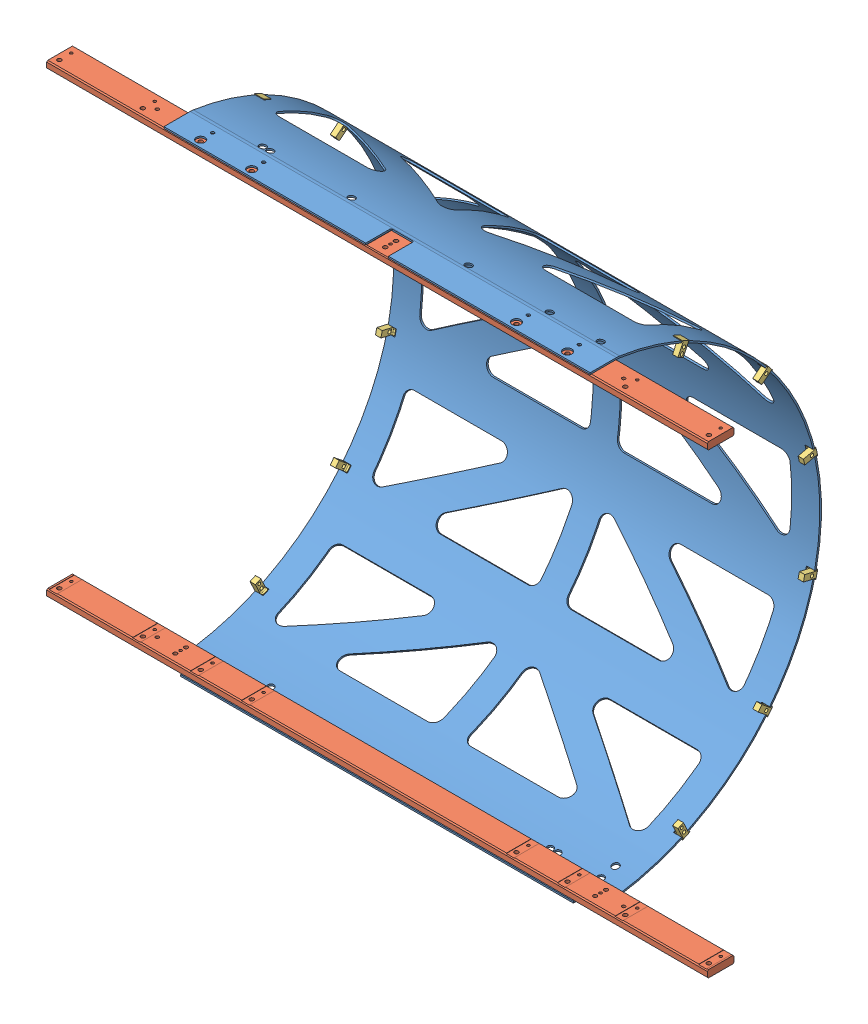
SolidWorks assembly VTX-Spaceframe Assy, configuration Default. Lengths in mm.
Overall size (600 431.91 213.56).
16 component instances, 4 part files, 14 mates.
Components (placement in the parent):
- VTX-Spaceframe Shell-1: VTX-Spaceframe Shell [Default] at origin size (393.6 431.91 213.56)
- VTX-Barrel Spaceframe joint tab-16: VTX-Barrel Spaceframe joint tab [top] at origin size (600 6.71 24.73)
- VTX-Barrel Spaceframe joint tab-15: VTX-Barrel Spaceframe joint tab [bottom] x (-1 0 0) z (0 0 1) size (600 6.71 24.73)
- Spaceframe disk mounting block 1-8: Spaceframe disk mounting block 1 [pin-threaded holes] at (195.09 -191.7412 -89.4104) x (0 -0.422618 0.906308) z (0 0.906308 0.422618) size (7.5 8.75 12)
- Spaceframe disk mounting block 1-2: Spaceframe disk mounting block 1 [pin-threaded holes] at (-195.09 -191.7412 -89.4104) x (0 0.422618 -0.906308) z (0 0.906308 0.422618) size (7.5 8.75 12)
- Spaceframe disk mounting block 1-9: Spaceframe disk mounting block 1 [threaded hole only] at (195.09 -133.1409 -164.4153) x (0 -0.777146 0.62932) z (0 0.62932 0.777146) size (7.5 8.75 12)
- Spaceframe disk mounting block 1-10: Spaceframe disk mounting block 1 [threaded hole only] at (195.09 -47.5913 -206.1407) x (0 -0.97437 0.224951) z (0 0.224951 0.97437) size (7.5 8.75 12)
- Spaceframe disk mounting block 1-11: Spaceframe disk mounting block 1 [threaded hole only] at (195.09 47.5913 -206.1407) x (0 -0.97437 -0.224951) z (0 -0.224951 0.97437) size (7.5 8.75 12)
- Spaceframe disk mounting block 1-12: Spaceframe disk mounting block 1 [threaded hole only] at (195.09 133.1409 -164.4153) x (0 -0.777146 -0.62932) z (0 -0.62932 0.777146) size (7.5 8.75 12)
- Spaceframe disk mounting block 1-13: Spaceframe disk mounting block 1 [slot for pin + threaded hole] at (195.09 191.7412 -89.4104) x (0 -0.422618 -0.906308) z (0 -0.906308 0.422618) size (7.5 8.75 12)
- Spaceframe disk mounting block 1-14: Spaceframe disk mounting block 1 [threaded hole only] at (-195.09 -133.1409 -164.4153) x (0 0.777146 -0.62932) z (0 0.62932 0.777146) size (7.5 8.75 12)
- Spaceframe disk mounting block 1-15: Spaceframe disk mounting block 1 [threaded hole only] at (-195.09 -47.5913 -206.1407) x (0 0.97437 -0.224951) z (0 0.224951 0.97437) size (7.5 8.75 12)
- Spaceframe disk mounting block 1-16: Spaceframe disk mounting block 1 [threaded hole only] at (-195.09 47.5913 -206.1407) x (0 0.97437 0.224951) z (0 -0.224951 0.97437) size (7.5 8.75 12)
- Spaceframe disk mounting block 1-17: Spaceframe disk mounting block 1 [threaded hole only] at (-195.09 133.1409 -164.4153) x (0 0.777146 0.62932) z (0 -0.62932 0.777146) size (7.5 8.75 12)
- Spaceframe disk mounting block 1-18: Spaceframe disk mounting block 1 [slot for pin + threaded hole] at (-195.09 191.7412 -89.4104) x (0 0.422618 0.906308) z (0 -0.906308 0.422618) size (7.5 8.75 12)
- Adhesive-1: Adhesive [Default] at origin
Mates (geometry in assembly coordinates):
- Coincident77: coincident aligned: plane of VTX-Barrel Spaceframe joint tab-16 through (0 0 0) normal (0 0 1); plane of assembly through (0 0 0) normal (0 0 1)
- Coincident78: coincident aligned: plane of VTX-Barrel Spaceframe joint tab-16 through (0 0 0) normal (0 1 0); plane of assembly through (0 0 0) normal (0 1 0)
- Coincident79: coincident aligned: plane of VTX-Barrel Spaceframe joint tab-16 through (0 0 0) normal (1 0 0); plane of assembly through (0 0 0) normal (1 0 0)
- Coincident80: coincident anti-aligned: plane of VTX-Barrel Spaceframe joint tab-15; plane of assembly through (0 0 0) normal (1 0 0)
- Coincident81: coincident aligned: plane of VTX-Barrel Spaceframe joint tab-15 through (0 0 0) normal (0 0 1); plane of assembly through (0 0 0) normal (0 0 1)
- Coincident82: coincident anti-aligned: plane of VTX-Barrel Spaceframe joint tab-15; plane of assembly through (0 0 0) normal (0 1 0)
- Coincident84: coincident: plane of Spaceframe disk mounting block 1-8; line of assembly
- Angle1: planar angle = 0.436332 rad aligned: plane of assembly through (0 0 0) normal (0 0 1); plane of Spaceframe disk mounting block 1-8
- Distance1: distance = 214.063 mm: line of assembly; line of Spaceframe disk mounting block 1-8 through (191.3822 -194.007 -90.4669) axis (1 0 0)
- Coincident88: coincident: plane of Spaceframe disk mounting block 1-2; line of assembly
- Angle2: planar angle = 0.436332 rad anti-aligned: plane of assembly through (0 0 0) normal (0 0 1); plane of Spaceframe disk mounting block 1-2
- Distance2: distance = 214.063 mm: line of assembly; line of Spaceframe disk mounting block 1-2 through (-191.3822 -194.007 -90.4669) axis (-1 0 0)
- Coincident89: coincident aligned: plane of Spaceframe disk mounting block 1-8 through (197.59 -186.0475 -89.7896) normal (1 0 0); plane of assembly through (197.59 0 0) normal (1 0 0)
- Coincident90: coincident anti-aligned: plane of Spaceframe disk mounting block 1-2 through (-197.59 -188.3719 -84.8049) normal (-1 0 0); sketch_entity of ?
